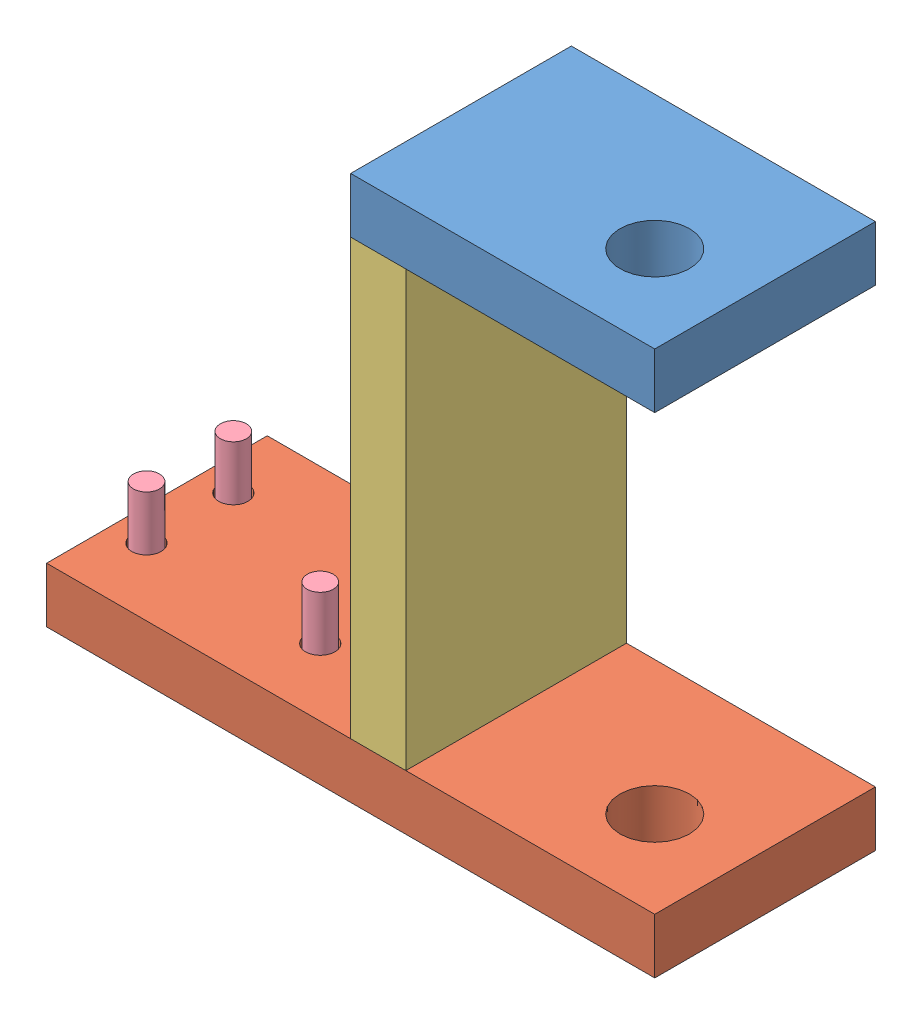
SolidWorks assembly 51model, configuration Default. Lengths in mm.
Overall size (280 262.8 101.6).
7 component instances, 4 part files, 12 mates.
Components (placement in the parent):
- ShortSupportFlat-1: ShortSupportFlat [Default] at (274.3548 16.731 95.8509) x (0 -1 0) z (0 0 1) size (25.4 140 101.6)
- LongSupportFlat-1: LongSupportFlat [Default] at (414.3548 -234.069 95.8509) x (0 0 -1) z (1 0 0) size (101.6 25.4 280)
- 26model-1: 26model [Default] at (299.7548 -208.669 95.8509) x (0 1 0) z (0 0 1) size (200 25.4 101.6)
- LongScrew-1: LongScrew [Default] at (229.3548 -246.069 64.8509) size (18 62 18)
- LongScrew-2: LongScrew [Default] at (229.3548 -246.069 24.8509) size (18 62 18)
- LongScrew-3: LongScrew [Default] at (149.3548 -246.069 64.8509) size (18 62 18)
- LongScrew-4: LongScrew [Default] at (149.3548 -246.069 24.8509) size (18 62 18)
Mates (geometry in assembly coordinates):
- Coincident2: coincident anti-aligned: plane of ShortSupportFlat-1 through (414.3548 -8.669 95.8509) normal (0 -1 0); plane of 26model-1 through (274.3548 -8.669 95.8509) normal (0 1 0)
- Coincident3: coincident aligned: plane of ShortSupportFlat-1 through (414.3548 16.731 -5.7491) normal (0 0 -1); plane of 26model-1 through (274.3548 -208.669 -5.7491) normal (0 0 -1)
- Coincident4: coincident aligned: plane of ShortSupportFlat-1 through (274.3548 16.731 -5.7491) normal (-1 0 0); plane of 26model-1 through (274.3548 -208.669 -5.7491) normal (-1 0 0)
- Coincident5: coincident anti-aligned: plane of LongSupportFlat-1 through (134.3548 -208.669 95.8509) normal (0 1 0); plane of 26model-1 through (274.3548 -208.669 95.8509) normal (0 -1 0)
- Coincident6: coincident aligned: plane of LongSupportFlat-1 through (414.3548 -208.669 -5.7491) normal (0 0 -1); plane of 26model-1 through (274.3548 -208.669 -5.7491) normal (0 0 -1)
- Coincident7: coincident aligned: plane of ShortSupportFlat-1 through (414.3548 16.731 -5.7491) normal (1 0 0); plane of LongSupportFlat-1 through (414.3548 -208.669 95.8509) normal (1 0 0)
- Coincident10: coincident anti-aligned: plane of LongSupportFlat-1 through (134.3548 -234.069 95.8509) normal (0 -1 0); plane of LongScrew-3 through (149.3548 -234.069 64.8509) normal (0 1 0)
- Coincident11: coincident anti-aligned: plane of LongSupportFlat-1 through (134.3548 -234.069 95.8509) normal (0 -1 0); plane of LongScrew-4 through (149.3548 -234.069 24.8509) normal (0 1 0)
- Coincident12: coincident: circle of LongSupportFlat-1; cylinder of LongScrew-2 through (229.3548 -184.069 24.8509) axis (0 -1 0) radius 6
- Coincident13: coincident: circle of LongSupportFlat-1; cylinder of LongScrew-1 through (229.3548 -184.069 64.8509) axis (0 -1 0) radius 6
- Coincident14: coincident: circle of LongSupportFlat-1; cylinder of LongScrew-4 through (149.3548 -184.069 24.8509) axis (0 -1 0) radius 6
- Coincident15: coincident: circle of LongSupportFlat-1; cylinder of LongScrew-3 through (149.3548 -184.069 64.8509) axis (0 -1 0) radius 6
